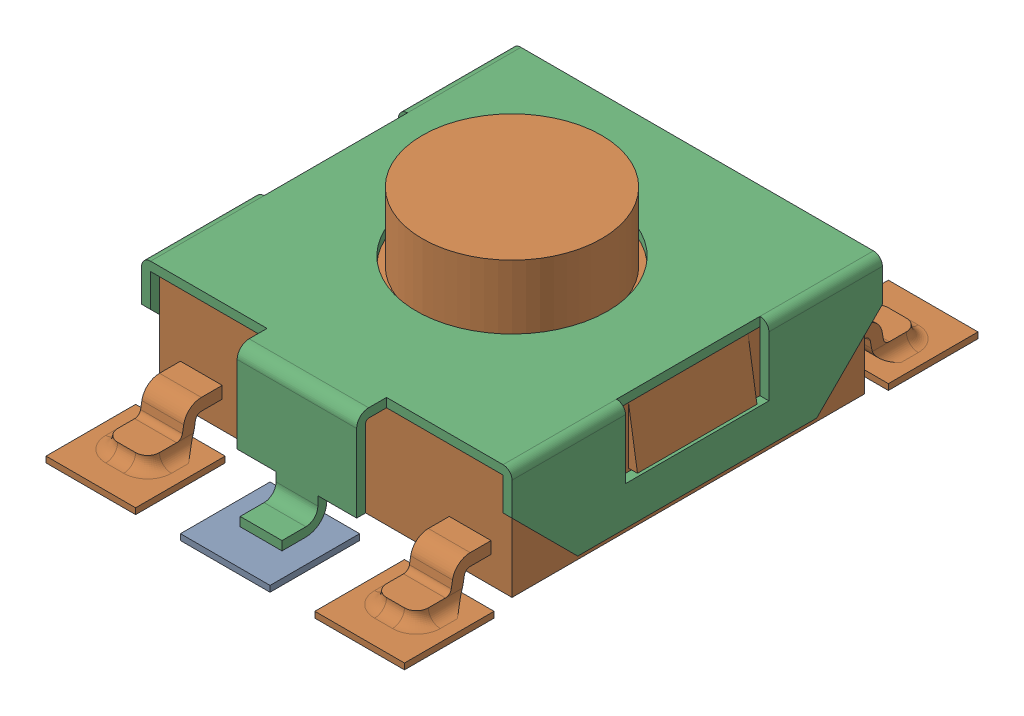
SolidWorks assembly micro RESET BUTTON, configuration Predeterminado. Lengths in mm.
Overall size (6.2 3.1 9.6).
2 component instances, 2 part files, 0 mates.
Components (placement in the parent):
- micro RESET CORE-1: micro RESET CORE [Predeterminado] at (0 0.1 0) x (-1 0 0) z (0 0 -1) size (6.2 3.1 9.6)
- micro RESET-1: micro RESET [Predeterminado] at (0 0.1 0) x (0 0 1) z (-1 0 0) size (7.3 2 6.2)
